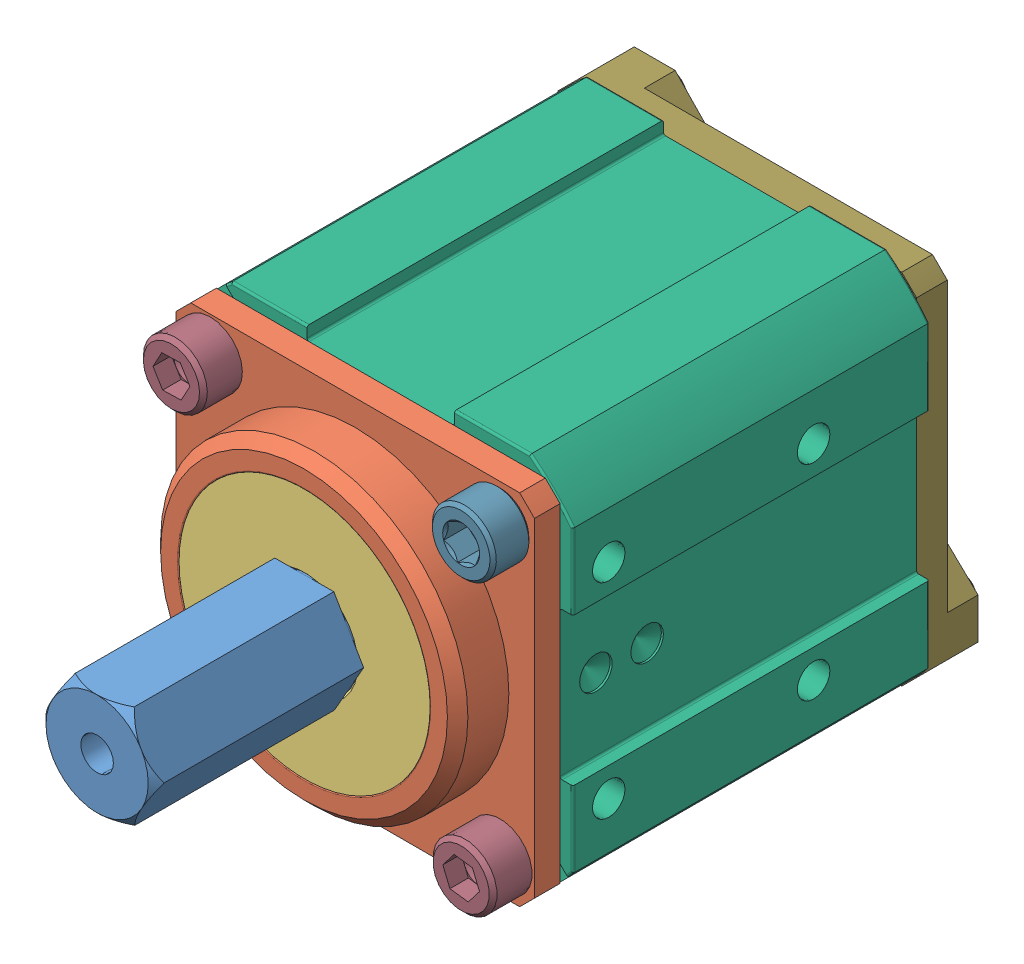
SolidWorks assembly am-3754+-+16_1+-+57+Sport, configuration Default. Lengths in mm.
Overall size (47.68 47.68 89.15).
26 component instances, 14 part files, 0 mates.
Components (placement in the parent):
- am-XXXX - 57 Sport 500 Hex Output Plug-1: am-XXXX - 57 Sport 500 Hex Output Plug [Default] at (20.4435 33.6564 37.638) size (44.45 44.45 56.9)
  - am-XXXX - 57 Sport 500 Hex Shaft-1: am-XXXX - 57 Sport 500 Hex Shaft [Default] at (0 0 6.2738) x (0.999982 0.006056 0) z (0 0 1) size (16.1 12.67 56.9)
  - Output Block-1: Output Block [Default] at origin size (44.45 44.45 20.32)
  - FR8ZZ Bearing-1: FR8ZZ Bearing [Default] at (8.9053 -5.9773 -13.8938) x (0.999973 0.007281 0) z (0 0 1) size (31.75 31.75 7.95)
  - FR8ZZ Bearing-2: FR8ZZ Bearing [Default] at (5.8713 8.9755 6.2738) x (0.923728 0.383049 0) z (0 0 -1) size (31.75 31.75 7.95)
  - retaining Ring 0500 - Mcm 98410A122_98410A122-1: retaining Ring 0500 - Mcm 98410A122_98410A122 [Default] at (0 0 -14.3891) x (0 0 1) z (-0.999848 0.017452 0) size (0.89 16.1 14.34)
- Thrust washer - 775 Sport-1: Thrust washer - 775 Sport [Default] at (20.4435 33.6564 -8.3472) x (0.883389 0.46864 0) z (0 0 1) size (31 31 1.52)
- am-XXXX - 57 Sport 2 Stage Ring Gear Housing-1: am-XXXX - 57 Sport 2 Stage Ring Gear Housing [Default] at (20.4435 33.6564 12.365) size (47.68 47.68 44.22)
- 4_1 Output Stage-1: 4_1 Output Stage [Default] at (-121.0068 37.1623 87.4176) x (-0.999982 -0.006056 0) z (0 0 -1) size (38.96 38.96 14.52)
  - 4_1 Output Stage Carrier Plate-1: 4_1 Output Stage Carrier Plate [Default] at (-141.4265 -4.3625 67.1279) size (30.99 30.99 14.52)
  - 16T Short Planet Gear-1: 16T Short Planet Gear [Default] at (-155.2063 -5.4237 83.0693) x (0 0 1) z (0.923728 0.383049 0) size (7 12.42 12.42)
  - 16T Short Planet Gear-2: 16T Short Planet Gear [Default] at (-142.4877 9.4173 83.0693) x (0 0 1) z (0.383049 -0.923728 0) size (7 12.42 12.42)
  - 16T Short Planet Gear-3: 16T Short Planet Gear [Default] at (-127.6467 -3.3013 83.0693) x (0 0 1) z (-0.923728 -0.383049 0) size (7 12.42 12.42)
  - 16T Short Planet Gear-4: 16T Short Planet Gear [Default] at (-140.3653 -18.1423 83.0693) x (0 0 1) z (-0.383049 0.923728 0) size (7 12.42 12.42)
- am-XXXX - 4_1 Stage-1: am-XXXX - 4_1 Stage [Default] at (20.4435 33.6564 5.7714) x (0.989319 0.145764 0) z (0 0 -1) size (38.96 38.96 19.84)
  - am-XXXX - 57 Sport Stage Carrier Plate-1: am-XXXX - 57 Sport Stage Carrier Plate [Default] at origin size (31.12 31.12 12.6)
  - 16T Sun Gear-1: 16T Sun Gear [Default] at (2.1233 -0.5181 -1.3921) x (0 0 -1) z (-1 0 0) size (12.75 12.42 12.42)
  - 16T Planet Gear-1: 16T Planet Gear [Default] at (-11.2886 -1.3776 8.289) x (0 0 1) z (0.923728 0.383049 0) size (7.09 12.42 12.42)
  - 16T Planet Gear-2: 16T Planet Gear [Default] at (-1.3776 11.2886 8.289) x (0 0 1) z (0.383049 -0.923728 0) size (7.09 12.42 12.42)
  - 16T Planet Gear-3: 16T Planet Gear [Default] at (11.2886 1.3776 8.289) x (0 0 1) z (-0.923728 -0.383049 0) size (7.09 12.42 12.42)
  - 16T Planet Gear-4: 16T Planet Gear [Default] at (1.3776 -11.2886 8.289) x (0 0 1) z (-0.383049 0.923728 0) size (7.09 12.42 12.42)
- am-3765 - 57 Sport Motor Block-1: am-3765 - 57 Sport Motor Block [Default] at (20.4435 33.6564 -13.543) x (0 1 0) z (0 0 1) size (45.76 47.07 8.89)
- 10-32x2250_shcs_HX-SHCS 0.19-32x1.375x1-C-1: 10-32x2250_shcs_HX-SHCS 0.19-32x1.375x1-C [Default] at (38.404 15.6959 42.464) x (0 0 -1) z (-0.923728 -0.383049 0) size (61.98 7.94 7.94)
- 10-32x2250_shcs_HX-SHCS 0.19-32x1.375x1-C-2: 10-32x2250_shcs_HX-SHCS 0.19-32x1.375x1-C [Default] at (2.483 51.6169 42.464) x (0 0 -1) z (-0.85131 -0.524663 0) size (61.98 7.94 7.94)
- 10-32 X 375 SHCS_90128A940-1: 10-32 X 375 SHCS_90128A940 [Default] at (38.404 51.6169 28.113) x (0.317538 -0.948246 0) z (0 0 -1) size (7.92 7.92 14.58)
- 10-32 X 375 SHCS_90128A940-2: 10-32 X 375 SHCS_90128A940 [Default] at (2.483 15.6959 28.113) x (0.463868 -0.885904 0) z (0 0 -1) size (7.92 7.92 14.58)
